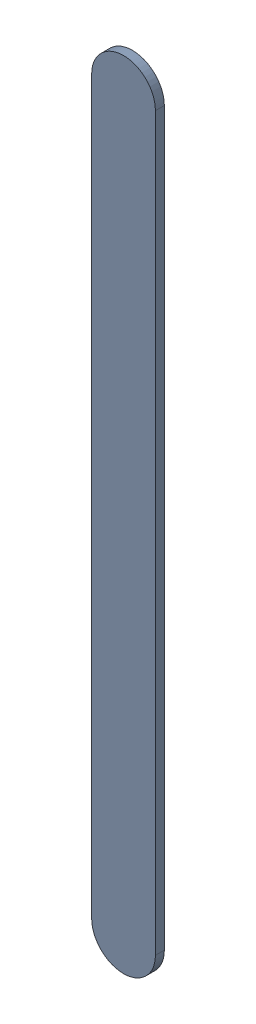
SolidWorks assembly Track (22.475mm,28.475mm)(22.475mm,31.391mm) on Top Layer, configuration Predeterminado. Lengths in mm.
Overall size (0.25 3.17 0.04).
2 component instances, 1 part files, 0 mates.
Components (placement in the parent):
- Track (22.475mm,28.475mm)(22.475mm,31.391mm) on Top Layer-1-1: Track (22.475mm,28.475mm)(22.475mm,31.391mm) on Top Layer-1 [Predeterminado] at (-68.317 -44.187 -0.0457) size (0.25 3.17 0.04)
  - Track (22.475mm,28.475mm)(22.475mm,31.391mm) on Top Layer-Part-1-1: Track (22.475mm,28.475mm)(22.475mm,31.391mm) on Top Layer-Part-1 [Predeterminado] at origin size (0.25 3.17 0.04)
